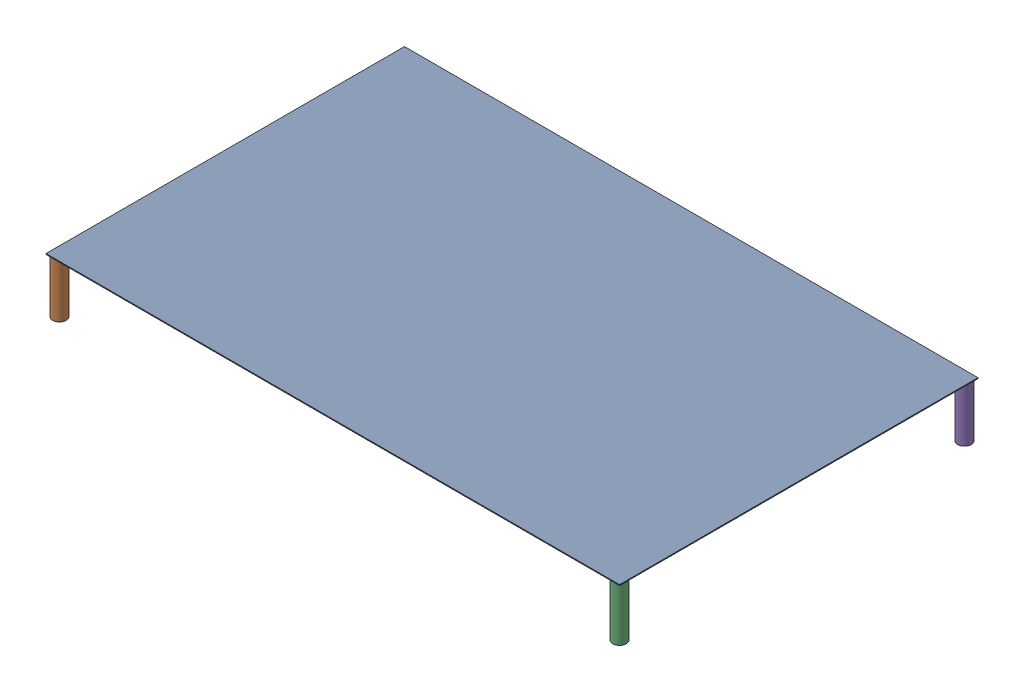
SolidWorks assembly Additional Tray Assembly, configuration Default. Lengths in mm.
Overall size (406.4 38.71 254).
5 component instances, 2 part files, 12 mates.
Components (placement in the parent):
- Perforated Tray-1: Perforated Tray [92725T36] at (-101.0573 1.4498 52.3416) size (406.4 0.61 254)
- Additional Tray Legs-1: Additional Tray Legs [8457K25] at (-299.4948 -17.905 174.5791) x (1 0 0) z (0 1 0) size (9.53 9.53 38.1)
- Additional Tray Legs-2: Additional Tray Legs [8457K25] at (97.3802 -17.905 174.5791) x (1 0 0) z (0 1 0) size (9.53 9.53 38.1)
- Additional Tray Legs-3: Additional Tray Legs [8457K25] at (-299.4948 -17.905 -69.8959) x (1 0 0) z (0 1 0) size (9.53 9.53 38.1)
- Additional Tray Legs-4: Additional Tray Legs [8457K25] at (97.3802 -17.905 -69.8959) x (1 0 0) z (0 1 0) size (9.53 9.53 38.1)
Mates (geometry in assembly coordinates):
- Coincident1: coincident anti-aligned: plane of Perforated Tray-1 through (-304.2573 1.145 179.3416) normal (0 -1 0); plane of Additional Tray Legs-2 through (97.3802 1.145 174.5791) normal (0 1 0)
- Coincident2: coincident anti-aligned: plane of Perforated Tray-1 through (-304.2573 1.145 179.3416) normal (0 -1 0); plane of Additional Tray Legs-3 through (-299.4948 1.145 -69.8959) normal (0 1 0)
- Coincident3: coincident anti-aligned: plane of Perforated Tray-1 through (-304.2573 1.145 179.3416) normal (0 -1 0); plane of Additional Tray Legs-1 through (-299.4948 1.145 174.5791) normal (0 1 0)
- Coincident4: coincident anti-aligned: plane of Perforated Tray-1 through (-304.2573 1.145 179.3416) normal (0 -1 0); plane of Additional Tray Legs-4 through (97.3802 1.145 -69.8959) normal (0 1 0)
- Tangent1: tangent aligned: plane of Perforated Tray-1 through (102.1427 1.145 179.3416) normal (1 0 0); cylinder of Additional Tray Legs-2 through (97.3802 1.145 174.5791) axis (0 -1 0) radius 4.7625
- Tangent2: tangent aligned: plane of Perforated Tray-1 through (-101.0573 1.4498 179.3416) normal (0 0 1); cylinder of Additional Tray Legs-2 through (97.3802 1.145 174.5791) axis (0 -1 0) radius 4.7625
- Tangent3: tangent aligned: plane of Perforated Tray-1 through (-101.0573 1.4498 179.3416) normal (0 0 1); cylinder of Additional Tray Legs-1 through (-299.4948 1.145 174.5791) axis (0 -1 0) radius 4.7625
- Tangent4: tangent aligned: plane of Perforated Tray-1 through (-304.2573 1.145 179.3416) normal (-1 0 0); cylinder of Additional Tray Legs-1 through (-299.4948 1.145 174.5791) axis (0 -1 0) radius 4.7625
- Tangent5: tangent aligned: plane of Perforated Tray-1 through (-304.2573 1.145 179.3416) normal (-1 0 0); cylinder of Additional Tray Legs-3 through (-299.4948 1.145 -69.8959) axis (0 -1 0) radius 4.7625
- Tangent6: tangent aligned: plane of Perforated Tray-1 through (-101.0573 1.4498 -74.6584) normal (0 0 -1); cylinder of Additional Tray Legs-3 through (-299.4948 1.145 -69.8959) axis (0 -1 0) radius 4.7625
- Tangent7: tangent aligned: plane of Perforated Tray-1 through (-101.0573 1.4498 -74.6584) normal (0 0 -1); cylinder of Additional Tray Legs-4 through (97.3802 1.145 -69.8959) axis (0 -1 0) radius 4.7625
- Tangent8: tangent aligned: plane of Perforated Tray-1 through (102.1427 1.145 179.3416) normal (1 0 0); cylinder of Additional Tray Legs-4 through (97.3802 1.145 -69.8959) axis (0 -1 0) radius 4.7625
